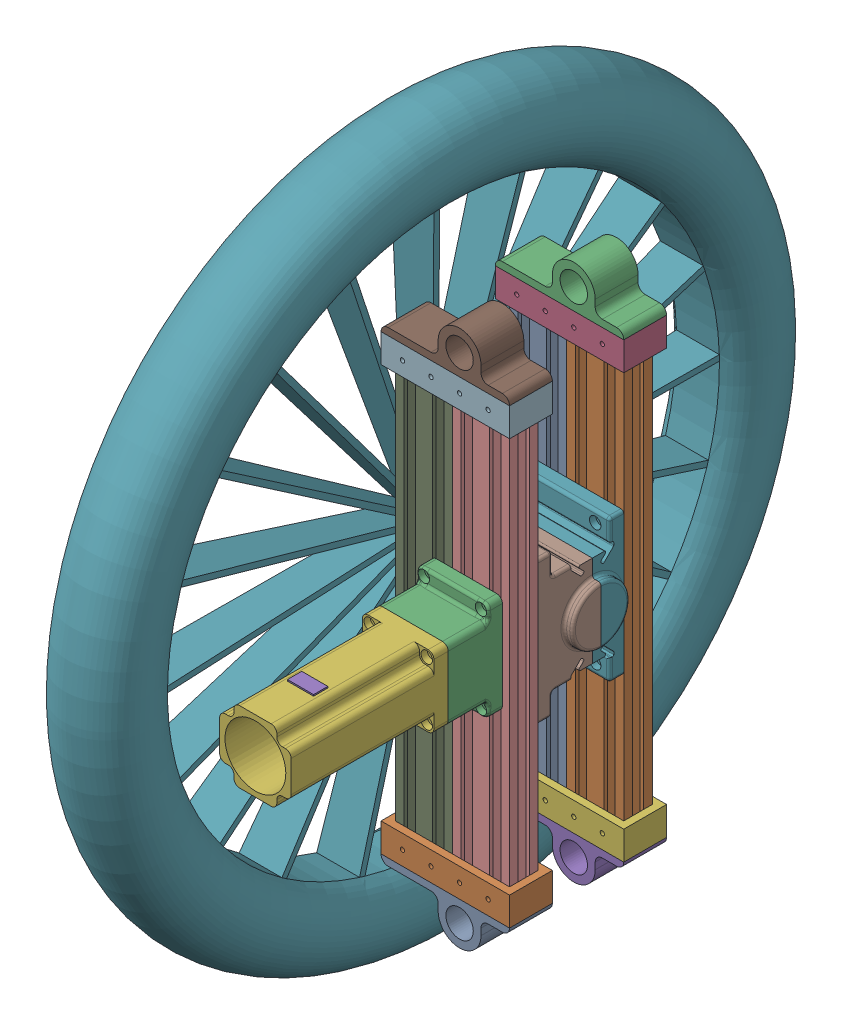
SolidWorks assembly Gearbox suspension, configuration Défaut. Lengths in mm.
Overall size (156.15 510.19 510.19).
17 component instances, 9 part files, 23 mates.
Components (placement in the parent):
- suspension1.0-1: suspension1.0 [Défaut] at (30.9469 -29.0306 -315) size (90 376 30)
  - profilé 370-40-1: profilé 370-40 [Défaut] at (-82.9768 -150.3226 340) size (40 316.8 20)
  - profilé 370-40-2: profilé 370-40 [Défaut] at (-42.9768 -150.3226 340) size (40 316.8 20)
  - fin profilé-1: fin profilé [Défaut] at (-62.9768 166.4774 330) x (-1 0 0) z (0 -1 0) size (90 30 49.6)
  - fin profilé-2: fin profilé [Défaut] at (-62.9768 -150.3226 330) x (-1 0 0) z (0 1 0) size (90 30 49.6)
- bot inf v2-1: bot inf v2 [Défaut] at (-72.0299 -70.9533 25) x (0 -1 0) z (-1 0 0) size (100 22 86.15)
- bot sup v2-1: bot sup v2 [Défaut] at (-72.0299 29.0467 75) x (0 -1 0) z (-1 0 0) size (100 38 86.15)
- suspension1.0-2: suspension1.0 [Défaut] at (30.9469 -29.0306 -235) size (90 376 30)
  - profilé 370-40-1: profilé 370-40 [Défaut] at (-82.9768 -150.3226 340) size (40 316.8 20)
  - profilé 370-40-2: profilé 370-40 [Défaut] at (-42.9768 -150.3226 340) size (40 316.8 20)
  - fin profilé-1: fin profilé [Défaut] at (-62.9768 166.4774 330) x (-1 0 0) z (0 -1 0) size (90 30 49.6)
  - fin profilé-2: fin profilé [Défaut] at (-62.9768 -150.3226 330) x (-1 0 0) z (0 1 0) size (90 30 49.6)
- top avec fenetre-1: top avec fenetre [Défaut] at (-47.0299 14.0467 105) x (0 -1 0) z (-1 0 0) size (70 38 50.62)
- adapt-1: adapt [Défaut] at (-22.0299 -20.9533 118) size (30 30 25)
- moteur-1: moteur [Défaut] at (-22.0299 -20.9533 221.4) x (1 0 0) z (0 0 -1) size (42 47 91.4)
- top ancien moteur-1: top ancien moteur [Défaut] at (-47.0299 -45.9533 143) x (1 0 0) z (0 -1 0) size (50 110 50)
- Roues-1: Roues [Défaut] at (-112.0299 -20.9533 47) x (0 -0.999788 -0.020585) z (0 -0.020585 0.999788) size (500 85 500)
Mates (geometry in assembly coordinates):
- Coïncidente1: coincident anti-aligned: plane of suspension1.0-1/profilé 370-40-1 through (-52.0299 137.4467 25) normal (0 0 1); plane of bot inf v2-1 through (-72.0299 -70.9533 25) normal (0 0 -1)
- Coïncidente2: coincident: point of suspension1.0-1/profilé 370-40-1; unknown of bot inf v2-1
- Parallèle1: parallel anti-aligned: plane of suspension1.0-1/fin profilé-1 through (-32.0299 117.4467 15) normal (0 -1 0); plane of bot inf v2-1 through (-72.0299 29.0467 35) normal (0 1 0)
- Coïncidente4: coincident anti-aligned: plane of bot inf v2-1 through (-72.0299 -70.9533 47) normal (0 0 1); plane of bot sup v2-1 through (-72.0299 29.0467 47) normal (0 0 -1)
- Coïncidente5: coincident aligned: plane of bot inf v2-1 through (-72.0299 -70.9533 35) normal (-1 0 0); plane of bot sup v2-1 through (-72.0299 29.0467 85) normal (-1 0 0)
- Coïncidente6: coincident aligned: plane of bot inf v2-1 through (14.1201 -52.9533 25) normal (0 -1 0); plane of bot sup v2-1 through (14.1201 -52.9533 75) normal (0 -1 0)
- Coïncidente7: coincident anti-aligned: plane of bot sup v2-1 through (-72.0299 29.0467 85) normal (0 0 1); plane of suspension1.0-2/profilé 370-40-1 through (-52.0299 137.4467 85) normal (0 0 -1)
- Parallèle2: parallel anti-aligned: plane of bot sup v2-1 through (-72.0299 29.0467 85) normal (0 1 0); plane of suspension1.0-2/fin profilé-1 through (-32.0299 117.4467 95) normal (0 -1 0)
- Coïncidente9: coincident: unknown of bot sup v2-1; unknown of suspension1.0-2/profilé 370-40-1
- Coaxiale1: concentric anti-aligned: cylinder of bot sup v2-1 through (-22.0299 -20.9533 77) axis (0 0 -1) radius 21; cylinder of top avec fenetre-1 through (-22.0299 -20.9533 116) axis (0 0 1) radius 17.5
- Coïncidente10: coincident anti-aligned: plane of suspension1.0-2/profilé 370-40-2 through (-12.0299 137.4467 105) normal (0 0 1); plane of top avec fenetre-1 through (-47.0299 14.0467 105) normal (0 0 -1)
- Coaxiale2: concentric anti-aligned: cylinder of top avec fenetre-1 through (-22.0299 -20.9533 116) axis (0 0 1) radius 17.5; cylinder of adapt-1 through (-22.0299 -20.9533 143) axis (0 0 -1) radius 15
- Coïncidente11: coincident aligned: plane of top avec fenetre-1 through (-47.0299 14.0467 143) normal (0 0 1); plane of adapt-1 through (-22.0299 -20.9533 143) normal (0 0 1)
- Coïncidente12: coincident anti-aligned: plane of adapt-1 through (-26.0299 -20.9533 143) normal (1 0 0); plane of moteur-1 through (-26.0299 -20.9533 157.9526) normal (-1 0 0)
- Coaxiale4: concentric aligned: cylinder of top avec fenetre-1 through (-22.0299 -20.9533 116) axis (0 0 1) radius 17.5; cylinder of moteur-1 through (-22.0299 -20.9533 180.9526) axis (0 0 1) radius 21
- Coïncidente13: coincident anti-aligned: plane of top avec fenetre-1 through (-47.0299 14.0467 143) normal (0 0 1); plane of top moteur-1 through (-47.0299 -56.3533 143) normal (0 0 -1)
- Coïncidente18: coincident aligned: plane of top avec fenetre-1 through (-47.0299 4.0467 143) normal (0 1 0); plane of top ancien moteur-1 through (-47.0299 4.0467 180.9526) normal (0 1 0)
- Coïncidente19: coincident aligned: plane of top avec fenetre-1 through (2.9701 14.0467 115) normal (1 0 0); plane of top ancien moteur-1 through (2.9701 -45.9533 180.9526) normal (1 0 0)
- Coïncidente20: coincident anti-aligned: plane of moteur-1 through (-22.0299 -20.9533 180.9526) normal (0 0 -1); plane of top ancien moteur-1 through (-47.0299 -45.9533 180.9526) normal (0 0 1)
- Parallèle3: parallel aligned: plane of moteur-1 through (-22.0299 5.0467 239.3526) normal (0 1 0); plane of top ancien moteur-1 through (-47.0299 4.0467 180.9526) normal (0 1 0)
- Coaxiale5: concentric aligned: cylinder of bot inf v2-1 through (14.1201 -20.9533 47) axis (1 0 0) radius 8; cylinder of Roues-1 through (-82.0299 -20.9533 47) axis (1 0 0) radius 6
- Distance1: distance = 10 mm anti-aligned: plane of bot sup v2-1 through (-72.0299 29.0467 85) normal (-1 0 0); plane of Roues-1 through (-82.0299 -20.9533 47) normal (1 0 0)
- Coïncidente21: coincident anti-aligned: plane of top avec fenetre-1 through (-47.0299 14.0467 143) normal (0 0 1); plane of top ancien moteur-1 through (-47.0299 -45.9533 143) normal (0 0 -1)
